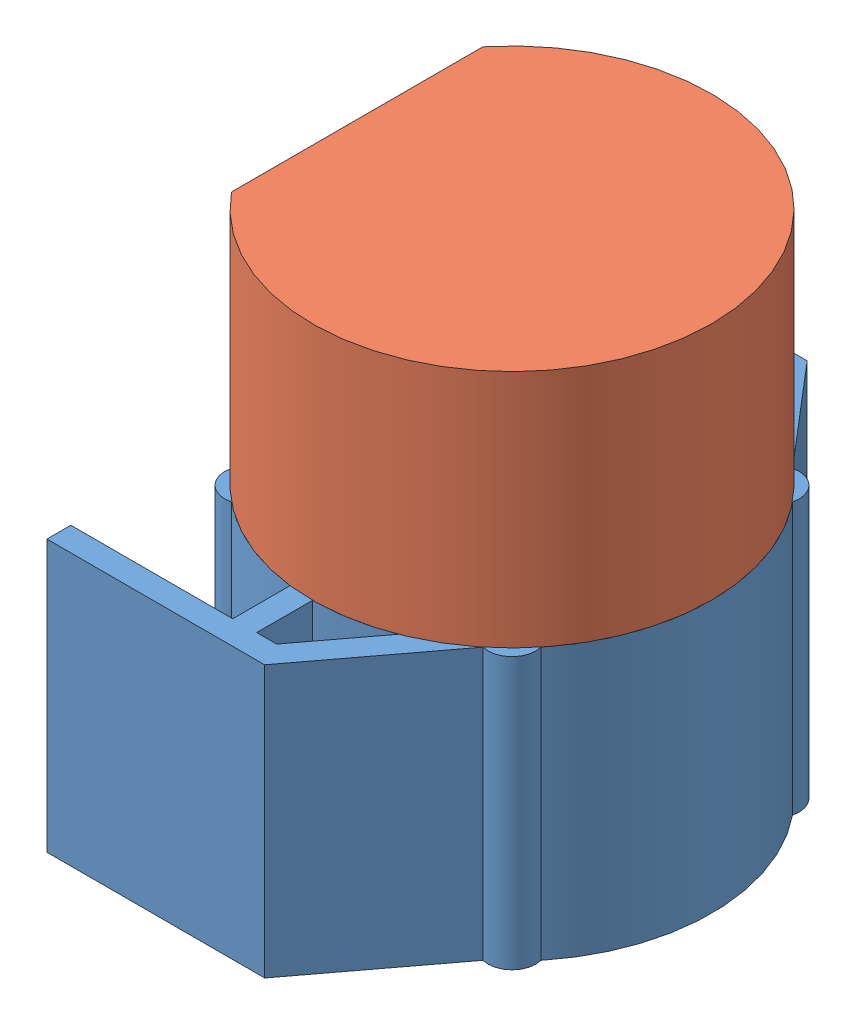
SolidWorks assembly PumpAssemv0_1, configuration Default. Lengths in mm.
Overall size (50 64 67).
2 component instances, 2 part files, 4 mates.
Components (placement in the parent):
- Tool holder-1: Tool holder [Default] at (7.0303 -121.5455 154.1964) size (50 34 67)
- Part1^PumpAssemv0_1-1: Part1^PumpAssemv0_1 [Default] at (7.0303 -87.5455 154.1964) x (1 0 0) z (0 1 0) size (44.41 50 64) (virtual)
Mates (geometry in assembly coordinates):
- InPlace1: in place: plane of Tool holder-1 through (7.0303 -87.5455 154.1964) normal (0 1 0); plane of ? through (0 -87.5455 0) normal (0 1 0); moOrthogonalPlaneRef_w of Tool holder-1 through (7.0303 -87.5455 154.1964) normal (0 1 0); plane of ? through (0 -87.5455 0) normal (0 0 -1); plane of Tool holder-1 through (7.0303 -87.5455 154.1964) normal (0 1 0); plane of ? through (0 -87.5455 0) normal (1 0 0); plane of Tool holder-1 through (7.0303 -87.5455 154.1964) normal (0 1 0); unknown of Part1^PumpAssemv0_1-1
- Coincident1: coincident aligned: plane of Tool holder-1; plane of Part1^PumpAssemv0_1-1
- Coincident2: coincident aligned: moOrthogonalPlaneRef_w of Tool holder-1 through (7.0303 -87.5455 154.1964) normal (0 0 -1); plane of Part1^PumpAssemv0_1-1 through (7.0303 -87.5455 154.1964) normal (0 0 -1)
- Coincident3: coincident anti-aligned: moOrthogonalPlaneRef_w of Tool holder-1 through (7.0303 -87.5455 154.1964) normal (-1 0 0); plane of Part1^PumpAssemv0_1-1 through (7.0303 -87.5455 154.1964) normal (1 0 0)
